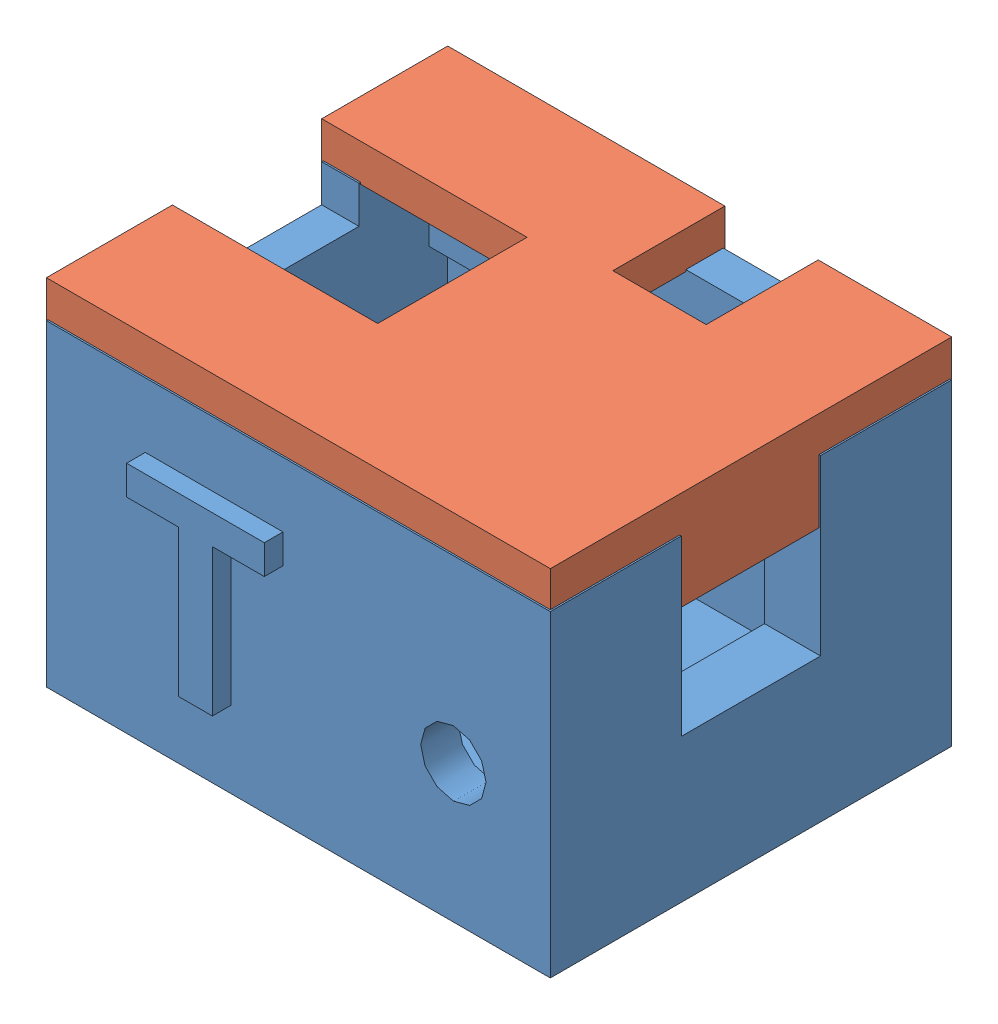
SolidWorks assembly Assem1_batt, configuration По умолчанию. Lengths in mm.
Overall size (28 18.91 22.59).
2 component instances, 2 part files, 0 mates.
Components (placement in the parent):
- bat_holder_part1-1: bat_holder_part1 [По умолчанию] at (6.1142 6.8807 14.0795) size (28 17 22.5)
- bat_holder_part2-1: bat_holder_part2 [По умолчанию] at (19.2584 23.7861 16.6965) size (27 5.3 21.5)
